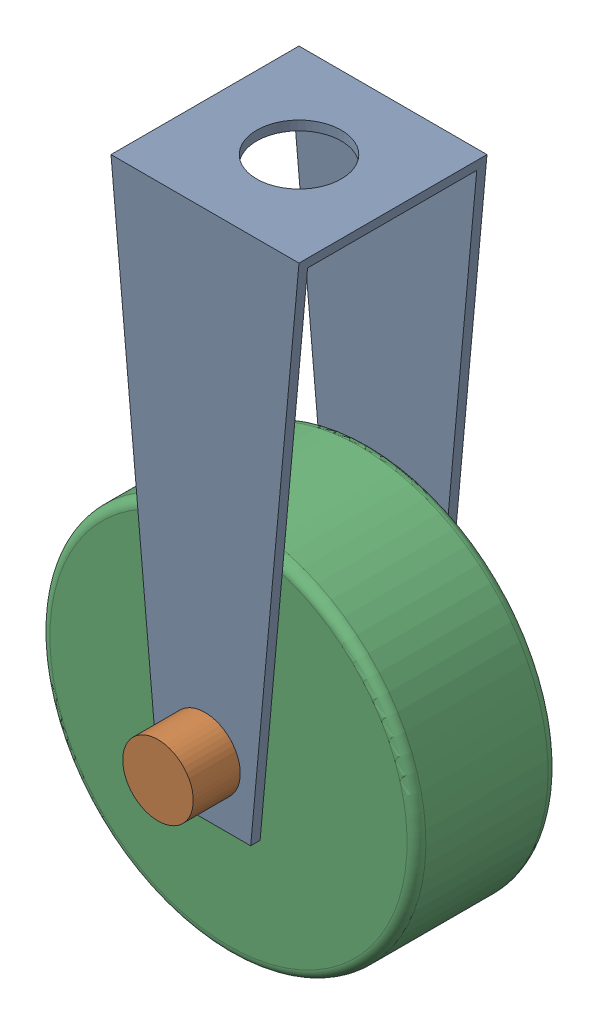
SolidWorks assembly Wheel Cutter Assembly, configuration Default. Lengths in mm.
Overall size (5.46 7.74 3).
3 component instances, 3 part files, 4 mates.
Components (placement in the parent):
- Roller Connecto-1: Roller Connecto [Default] at origin size (2 5.63 2)
- Roller Pin-1: Roller Pin [Default] at (1 -1.987 -1.5) x (0.994357 -0.106083 0) z (0 0 1) size (0.75 0.75 3)
- Roller Wheel-2: Roller Wheel [Default] at (1 -1.987 0.75) x (0.868271 -0.49609 0) z (0.49609 0.868271 0) size (4 1.5 4)
Mates (geometry in assembly coordinates):
- Concentric2: concentric anti-aligned: circle of Roller Connecto-1; cylinder of Roller Pin-1 through (1 -1.987 1) axis (0 0 -1) radius 0.25
- Coincident2: coincident anti-aligned: plane of Roller Connecto-1 through (2 -2.5976 1) normal (0 0 1); plane of Roller Pin-1 through (1 -1.987 1) normal (0 0 -1)
- Concentric3: concentric anti-aligned: cylinder of Roller Pin-1 through (1 -1.987 1) axis (0 0 -1) radius 0.25; cylinder of Roller Wheel-2 through (1 -1.987 -0.75) axis (0 0 1) radius 0.25
- Distance1: distance = 0.15 mm anti-aligned: plane of Roller Connecto-1 through (2 -2.5976 -0.9) normal (0 0 1); plane of Roller Wheel-2 through (1 -1.987 -0.75) normal (0 0 -1)
